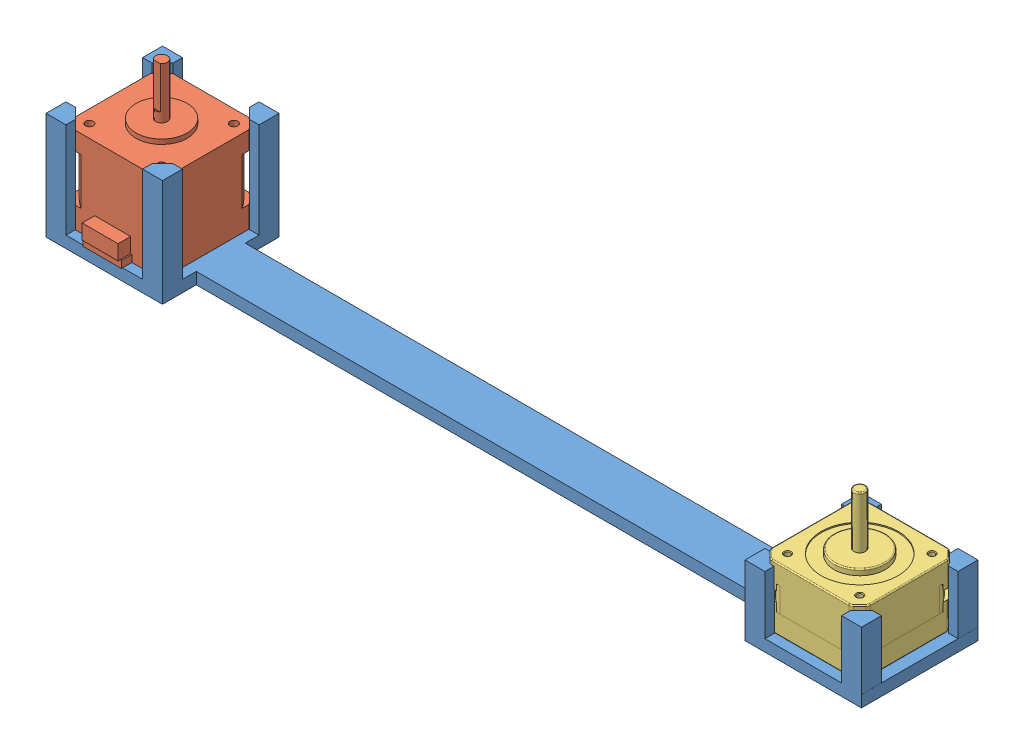
SolidWorks assembly Motors_and_base, configuration Default. Lengths in mm.
Overall size (350 66 51.4).
5 component instances, 3 part files, 6 mates.
Components (placement in the parent):
- Base-1: Base [Default] at (-342.2657 104.0697 352.9544) size (350 46 50)
- NEMA17-42A0C-1: NEMA17-42A0C [Default] at (-342.6565 146.0697 352.9544) x (1 0 -0.000019) z (0 1 0) size (42 47.4 61)
  - NEMA17-42A0C.step-1: NEMA17-42A0C.step [Default] at origin size (42 47.4 61)
    - NEMA17-42A02C-Body.step-1: NEMA17-42A02C-Body.step [Default] at origin size (42 47.4 61)
- NEMA_17_PHB42S28-406A v2-1: NEMA_17_PHB42S28-406A v2 [Default] at (-38.3321 1208.0697 367.9544) x (1 0 0) z (0 -1 0) size (42.3 42.3 51.3)
Mates (geometry in assembly coordinates):
- Tangent1: tangent: plane of Base-1 through (-323.546 150.0697 334.2347) normal (-0.707107 0 0.707107); cylinder of NEMA17-42A0C-1/NEMA17-42A0C.step-1/NEMA17-42A02C-Body.step-1 through (-342.6565 146.0697 352.9544) axis (0 1 0) radius 26.75
- Tangent2: tangent: plane of Base-1 through (-323.546 150.0697 371.6741) normal (-0.707107 0 -0.707107); cylinder of NEMA17-42A0C-1/NEMA17-42A0C.step-1/NEMA17-42A02C-Body.step-1 through (-342.6565 146.0697 352.9544) axis (0 1 0) radius 26.75
- Coincident1: coincident: plane of Base-1 through (-342.2657 109.0697 352.9544) normal (0 1 0); plane of NEMA17-42A0C-1/NEMA17-42A0C.step-1/NEMA17-42A02C-Body.step-1 through (-342.6564 109.0697 354.6554) normal (0 -1 0)
- Coincident2: coincident: plane of Base-1 through (-342.2657 109.0697 352.9544) normal (0 1 0); plane of NEMA_17_PHB42S28-406A v2-1 through (-43.0321 109.0697 352.9544) normal (0 -1 0)
- Coincident3: coincident: plane of Base-1 through (-173.5489 134.0697 521.6712) normal (-0.707107 0 -0.707107); plane of NEMA_17_PHB42S28-406A v2-1 through (-23.9321 121.0697 372.0544) normal (0.707107 0 0.707107)
- Coincident4: coincident: plane of Base-1 through (-173.5489 134.0697 184.2376) normal (-0.707107 0 0.707107); plane of NEMA_17_PHB42S28-406A v2-1 through (-23.9321 121.0697 333.8544) normal (0.707107 0 -0.707107)
